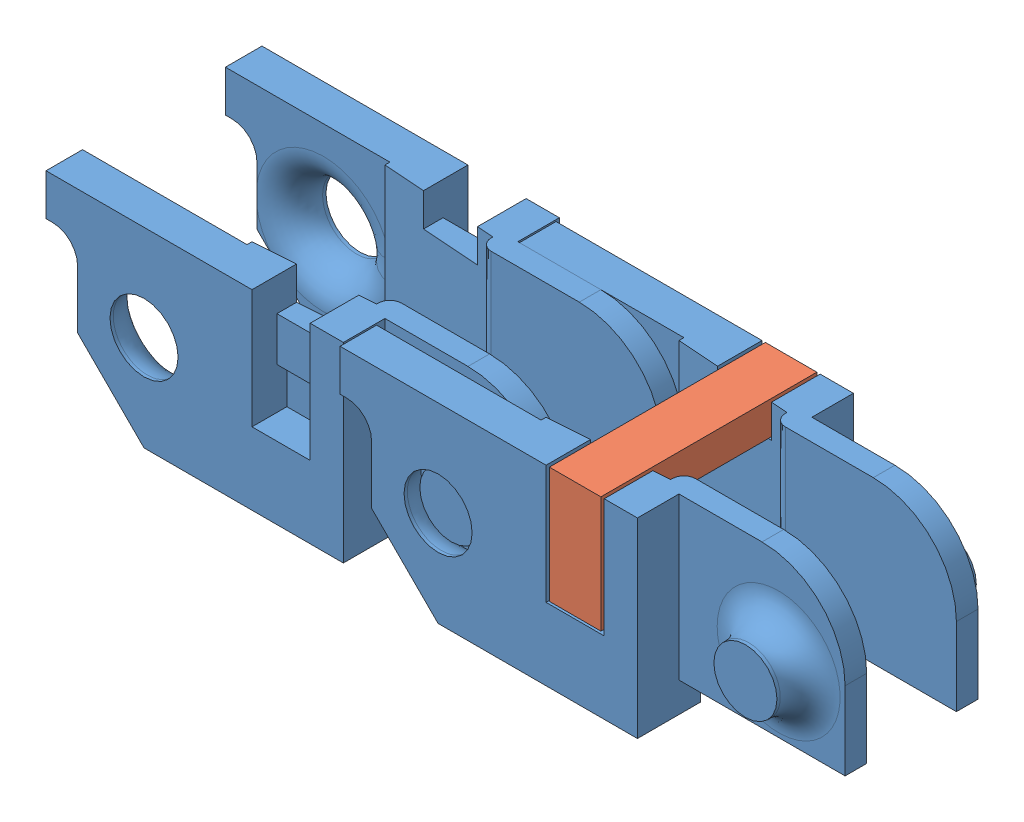
SolidWorks assembly Ensamblaje Eslobones, configuration Predeterminado. Lengths in mm.
Overall size (45.9 11.5 15).
3 component instances, 2 part files, 6 mates.
Components (placement in the parent):
- Eslabon 5 Bloqueado-1: Eslabon 5 Bloqueado [Predeterminado] at (-17.2246 -6.3756 23.5) size (27.9 11.5 13)
- Eslabon 5 Bloqueado-2: Eslabon 5 Bloqueado [Predeterminado] at (-35.2246 -6.3756 23.2) size (27.9 11.5 13)
- Cierre 5-1: Cierre 5 [Predeterminado] at (-6.5246 5.1244 34) x (1 0 0) z (0 0 -1) size (3.1 7 15)
Mates (geometry in assembly coordinates):
- Coincidente1: coincident anti-aligned: plane of Eslabon 5 Bloqueado-1 through (-18.7246 1.1244 23.2) normal (0 0 1); plane of Eslabon 5 Bloqueado-2 through (-9.2246 -4.8756 23.2) normal (0 0 -1)
- Coincidente2: coincident aligned: plane of Eslabon 5 Bloqueado-1 through (-17.2246 -6.3756 23.5) normal (0 -1 0); plane of Eslabon 5 Bloqueado-2 through (-35.2246 -6.3756 23.2) normal (0 -1 0)
- Concéntrica1: concentric aligned: circle of Eslabon 5 Bloqueado-1; circle of Eslabon 5 Bloqueado-2
- Coincidente3: coincident anti-aligned: plane of Eslabon 5 Bloqueado-1 through (-17.2246 3.1244 23.5) normal (0 1 0); plane of Cierre 5-1 through (-6.5246 3.1244 34) normal (0 -1 0)
- Coincidente4: coincident anti-aligned: plane of Eslabon 5 Bloqueado-1 through (-6.7246 -2.0256 22.5) normal (0 0 -1); plane of Cierre 5-1 through (-6.5246 -1.8756 22.5) normal (0 0 1)
- Distancia1: distance = 0.2 mm anti-aligned: plane of Cierre 5-1 through (-6.5246 3.1244 34) normal (-1 0 0); plane of Eslabon 5 Bloqueado-1 through (-6.7246 3.1244 21) normal (1 0 0)
